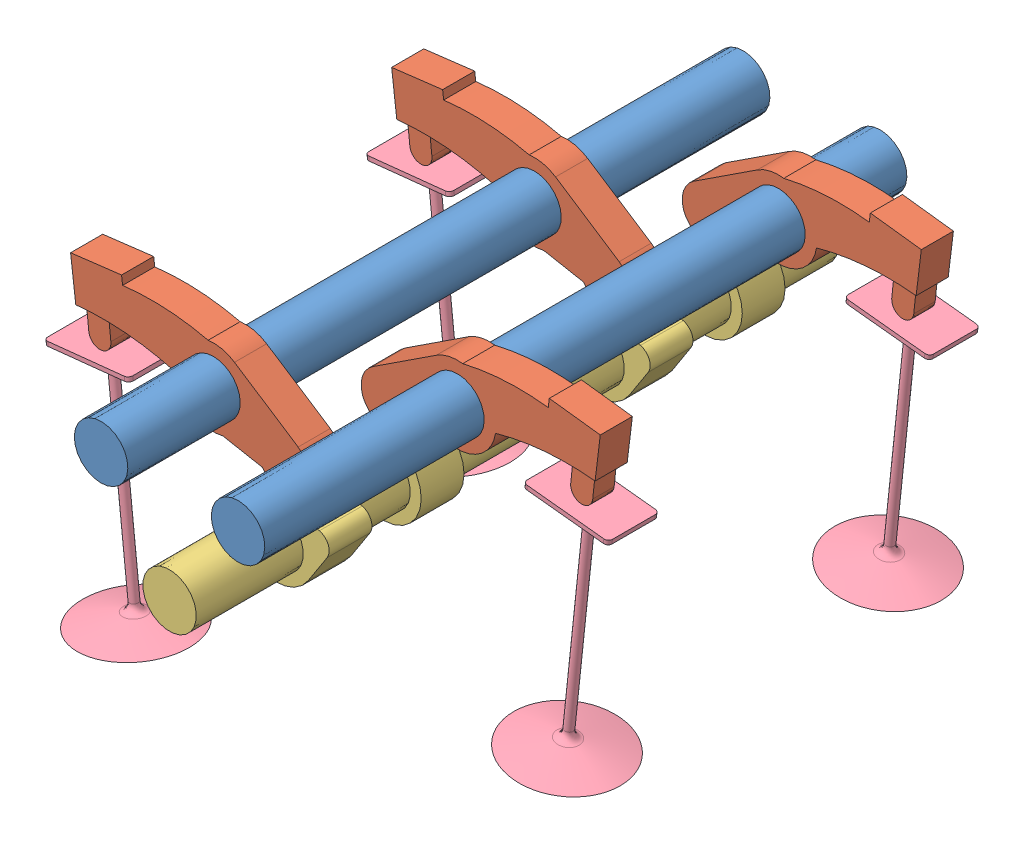
SolidWorks assembly Assem4, configuration Default. Lengths in mm.
Overall size (111.89 84.05 150).
11 component instances, 4 part files, 27 mates.
Components (placement in the parent):
- rocker arm mounting rod-4: rocker arm mounting rod [Default] at (-16 0 -150) x (-0.227118 0.973867 0) z (0 0 1) size (12.5 12.5 150)
- Part4-2: Part4 [Default] at (-16 0 -30) x (0.916315 -0.400458 0) z (0 0 1) size (58.8 26.64 7.5)
- rocker arm mounting rod-5: rocker arm mounting rod [Default] at (16 0 -150) x (0.84828 -0.529548 0) z (0 0 1) size (12.5 12.5 150)
- Part4-3: Part4 [Default] at (-16 0 -105) x (0.916315 -0.400458 0) z (0 0 1) size (58.8 26.64 7.5)
- Part4-4: Part4 [Default] at (16 0 -130) x (-0.916315 -0.400458 0) z (0 0 -1) size (58.8 26.64 7.5)
- Part4-5: Part4 [Default] at (16 0 -55) x (-0.916315 -0.400458 0) z (0 0 -1) size (58.8 26.64 7.5)
- cam 2-1: cam 2 [Default] at (0 -22 0) x (0.369892 -0.929075 0) z (0 0 -1) size (17.6 26 150)
- valve-1: valve [Default] at (-43.5133 -6.8525 -105) x (0.994477 0.10495 0) z (0.10495 -0.994477 0) size (25 25 54)
- valve-3: valve [Default] at (-43.5133 -6.8525 -30) x (0.994477 0.10495 0) z (0.10495 -0.994477 0) size (25 25 54)
- valve-4: valve [Default] at (43.5133 -6.8525 -55) x (0.994477 -0.10495 0) z (-0.10495 -0.994477 0) size (25 25 54)
- valve-5: valve [Default] at (43.5133 -6.8525 -130) x (0.994477 -0.10495 0) z (-0.10495 -0.994477 0) size (25 25 54)
Mates (geometry in assembly coordinates):
- Coincident10: coincident aligned: circle of rocker arm mounting rod-4
- Coincident13: coincident aligned: circle of rocker arm mounting rod-5
- Concentric5: concentric aligned: cylinder of rocker arm mounting rod-4 through (-16 0 0) axis (0 0 -1) radius 6.25; cylinder of Part4-2 through (-16 0 -26.25) axis (0 0 -1) radius 6.25
- Concentric6: concentric aligned: cylinder of rocker arm mounting rod-4 through (-16 0 0) axis (0 0 -1) radius 6.25; cylinder of Part4-3 through (-16 0 -101.25) axis (0 0 -1) radius 6.25
- Concentric7: concentric aligned: cylinder of rocker arm mounting rod-5 through (16 0 0) axis (0 0 -1) radius 6.25; circle of Part4-5
- Concentric8: concentric anti-aligned: cylinder of rocker arm mounting rod-5 through (16 0 0) axis (0 0 -1) radius 6.25; cylinder of Part4-4 through (16 0 -133.75) axis (0 0 1) radius 6.25
- Coincident17: coincident anti-aligned: circle of cam 2-1
- Width9: width anti-aligned: plane of cam 2-1 through (0.429 -12.0092 -25) normal (0 0 1); plane of Part4-2 through (0.429 -12.0092 -35) normal (0 0 -1); plane of cam 2-1 through (-16 0 -33.75) normal (0 0 -1); plane of Part4-2 through (-16 0 -26.25) normal (0 0 1)
- Width10: width anti-aligned: plane of cam 2-1 through (-0.429 -31.9908 -60) normal (0 0 -1); plane of Part4-5 through (-0.429 -31.9908 -50) normal (0 0 1); plane of cam 2-1 through (16 0 -51.25) normal (0 0 1); plane of Part4-5 through (16 0 -58.75) normal (0 0 -1)
- Width11: width anti-aligned: plane of cam 2-1 through (-0.429 -31.9908 -135) normal (0 0 -1); plane of Part4-4 through (-0.429 -31.9908 -125) normal (0 0 1); plane of cam 2-1 through (16 0 -126.25) normal (0 0 1); plane of Part4-4 through (16 0 -133.75) normal (0 0 -1)
- Width12: width anti-aligned: plane of cam 2-1 through (0.429 -12.0092 -110) normal (0 0 -1); plane of Part4-3 through (0.429 -12.0092 -100) normal (0 0 1); plane of cam 2-1 through (-16 0 -101.25) normal (0 0 1); plane of Part4-3 through (-16 0 -108.75) normal (0 0 -1)
- CamMateTangent9: cam tangent anti-aligned: cylinder of cam 2-1 through (0.429 -12.0092 -25) axis (0 0 -1) radius 3; cylinder of Part4-2 through (1.7304 -3.1038 -26.25) axis (0 0 -1) radius 6
- CamMateTangent10: cam tangent anti-aligned: cylinder of cam 2-1 through (-0.429 -31.9908 -50) axis (0 0 -1) radius 3; cylinder of Part4-5 through (-0.4937 -7.2082 -58.75) axis (0 0 1) radius 6
- CamMateTangent11: cam tangent anti-aligned: cylinder of cam 2-1 through (0.429 -12.0092 -100) axis (0 0 -1) radius 3; cylinder of Part4-3 through (1.7304 -3.1038 -101.25) axis (0 0 -1) radius 6
- CamMateTangent12: cam tangent anti-aligned: cylinder of cam 2-1 through (-0.429 -31.9908 -125) axis (0 0 -1) radius 3; cylinder of Part4-4 through (-0.4937 -7.2082 -133.75) axis (0 0 1) radius 6
- Tangent3: tangent anti-aligned: cylinder of Part4-3 through (-41.9854 -10.7271 -102.5) axis (0 0 -1) radius 2.5883; plane of valve-1 through (-32.6397 -10.1298 -100) normal (-0.337124 0.94146 0)
- Width15: width anti-aligned: plane of valve-1 through (-50.1903 -17.4766 -100) normal (-0.94146 -0.337124 0); plane of Part4-3 through (-31.3611 -10.7341 -100) normal (0.94146 0.337124 0); plane of valve-1 through (-39.5486 -9.8545 -102.5) normal (0.94146 0.337124 0); plane of Part4-3 through (-46.2204 -6.578 -102.5) normal (-0.94146 -0.337124 0)
- Width16: width anti-aligned: plane of valve-1 through (-49.2488 -17.1395 -111) normal (0 0 -1); plane of Part4-3 through (-49.2488 -17.1395 -99) normal (0 0 1); plane of valve-1 through (-41.9854 -10.7271 -102.5) normal (0 0 1); plane of Part4-3 through (-41.9854 -10.7271 -107.5) normal (0 0 -1)
- Width19: width anti-aligned: plane of valve-3 through (-49.2488 -17.1395 -24) normal (0 0 1); plane of Part4-2 through (-49.2488 -17.1395 -36) normal (0 0 -1); plane of valve-3 through (-41.9854 -10.7271 -27.5) normal (0 0 1); plane of Part4-2 through (-41.9854 -10.7271 -32.5) normal (0 0 -1)
- Width20: width aligned: plane of valve-3 through (-50.1903 -17.4766 -25) normal (-0.94146 -0.337124 0); plane of Part4-2 through (-31.3611 -10.7341 -25) normal (0.94146 0.337124 0); plane of valve-3 through (-46.2204 -6.578 -27.5) normal (-0.94146 -0.337124 0); plane of Part4-2 through (-39.5486 -9.8545 -27.5) normal (0.94146 0.337124 0)
- Tangent5: tangent anti-aligned: cylinder of Part4-2 through (-41.9854 -10.7271 -27.5) axis (0 0 -1) radius 2.5883; plane of valve-3 through (-32.6397 -10.1298 -25) normal (-0.337124 0.94146 0)
- Tangent6: tangent anti-aligned: cylinder of Part4-5 through (43.785 -4.2785 -57.5) axis (0 0 1) radius 2.5883; plane of valve-4 through (52.4636 -7.7971 -50) normal (0.10495 0.994477 0)
- Width21: width anti-aligned: plane of valve-4 through (53.3532 -8.8965 -50) normal (0.994477 -0.10495 0); plane of Part4-5 through (33.4636 -6.7975 -50) normal (-0.994477 0.10495 0); plane of valve-4 through (41.211 -4.0069 -57.5) normal (-0.994477 0.10495 0); plane of Part4-5 through (46.9188 0.7544 -57.5) normal (0.994477 -0.10495 0)
- Width22: width anti-aligned: plane of valve-4 through (34.4581 -6.9024 -49) normal (0 0 1); plane of Part4-5 through (34.4581 -6.9024 -61) normal (0 0 -1); plane of valve-4 through (43.785 -4.2785 -57.5) normal (0 0 -1); plane of Part4-5 through (43.785 -4.2785 -52.5) normal (0 0 1)
- Tangent7: tangent: cylinder of Part4-4 through (43.785 -4.2785 -132.5) axis (0 0 1) radius 2.5883; plane of valve-5 through (52.4636 -7.7971 -125) normal (0.10495 0.994477 0)
- Width23: width: plane of valve-5 through (53.3532 -8.8965 -125) normal (0.994477 -0.10495 0); plane of Part4-4 through (33.4636 -6.7975 -125) normal (-0.994477 0.10495 0); plane of valve-5 through (41.211 -4.0069 -132.5) normal (-0.994477 0.10495 0); plane of Part4-4 through (46.9188 0.7544 -132.5) normal (0.994477 -0.10495 0)
- Width24: width anti-aligned: plane of valve-5 through (34.4581 -6.9024 -136) normal (0 0 -1); plane of Part4-4 through (34.4581 -6.9024 -124) normal (0 0 1); plane of valve-5 through (43.785 -4.2785 -127.5) normal (0 0 1); plane of Part4-4 through (43.785 -4.2785 -132.5) normal (0 0 -1)
